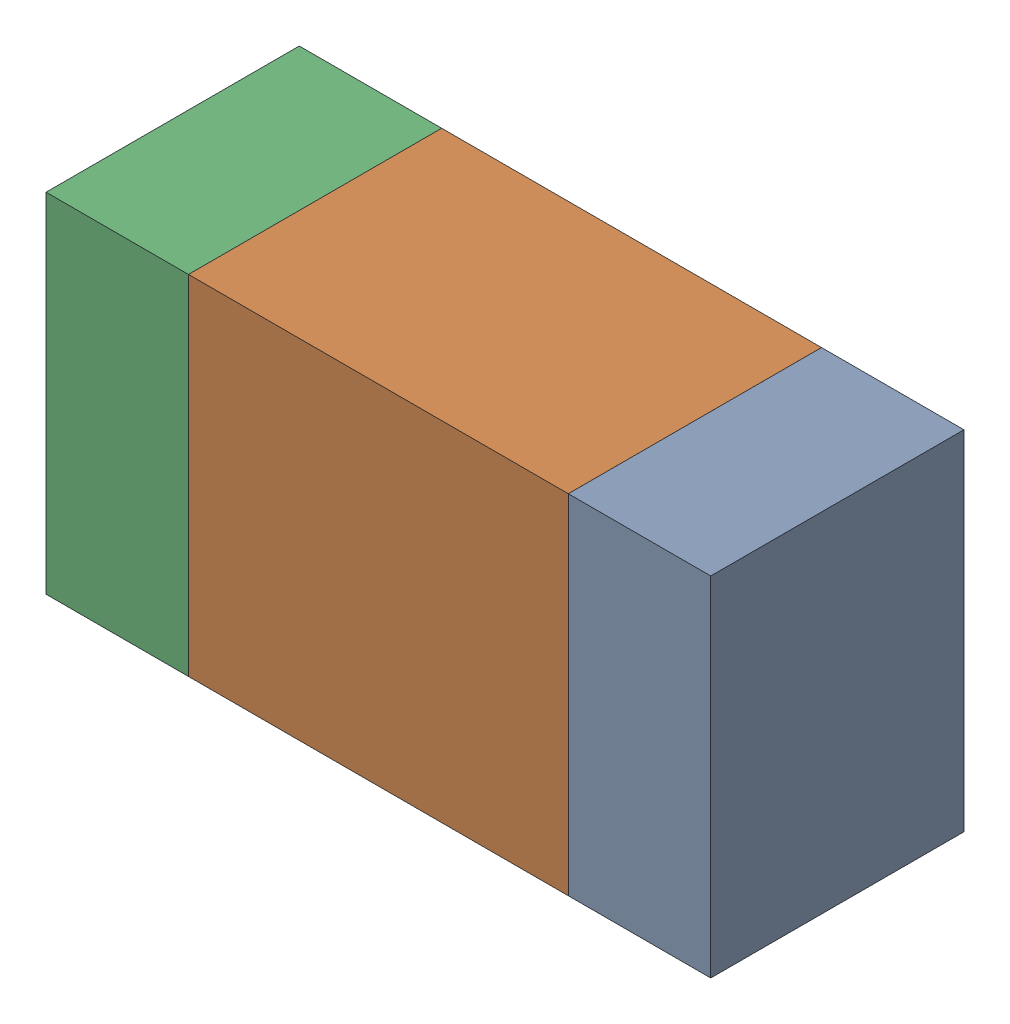
SolidWorks assembly R506_2PCB, configuration Default. Lengths in mm.
Overall size (1.05 0.55 0.4).
6 component instances, 2 part files, 0 mates.
Components (placement in the parent):
- 854785432-1: 854785432 [Default] at (147.1126 91.9001 0) size (0.22 0.55 0.4)
  - Extruded-1: Extruded [Default] at origin size (0.22 0.55 0.4)
- 854785568-1: 854785568 [Default] at (146.7001 91.9001 0) size (0.6 0.55 0.4)
  - Extruded_2-1: Extruded_2 [Default] at origin size (0.6 0.55 0.4)
- 854785432-2: 854785432 [Default] at (146.2876 91.9001 0) size (0.22 0.55 0.4)
  - Extruded-1: Extruded [Default] at origin size (0.22 0.55 0.4)
